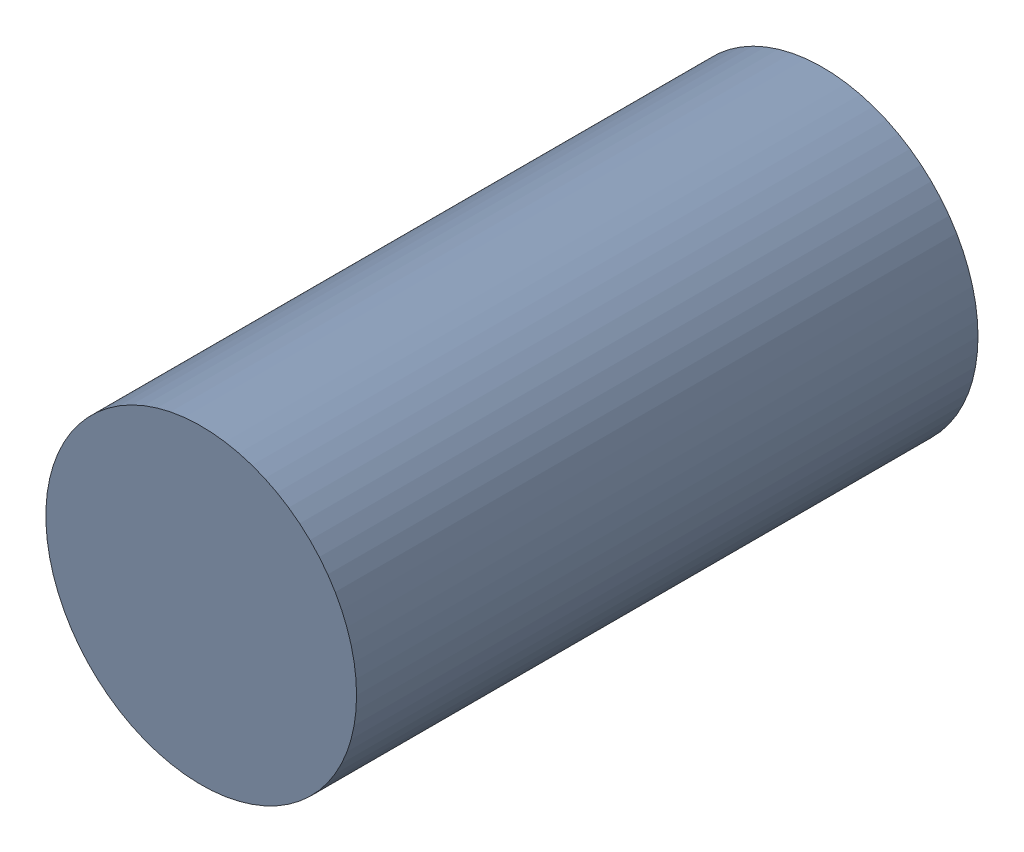
SolidWorks assembly MH9_1.step, configuration Default. Lengths in mm.
Overall size (1 1 2).
2 component instances, 1 part files, 0 mates.
Components (placement in the parent):
- 9228463120_1.step-11: 9228463120_1.step [Default] at (476 317 -1.5) size (1 1 2)
  - Cylinder_1.step-98: Cylinder_1.step [Default] at origin size (1 1 2)
